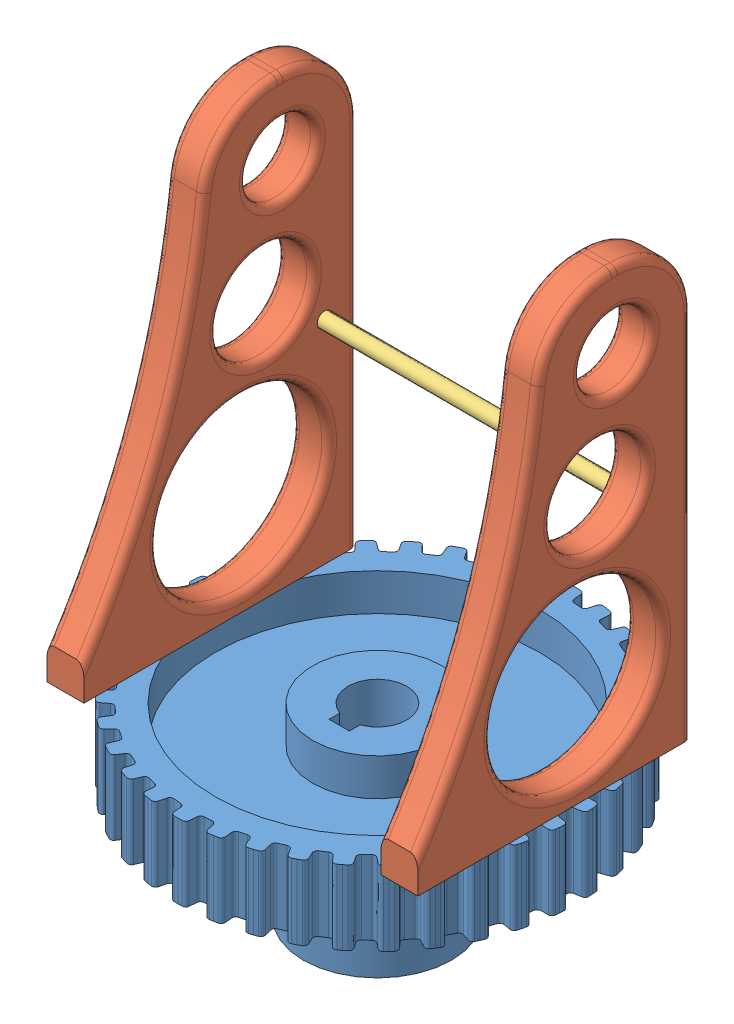
SolidWorks assembly Assem1, configuration Default. Lengths in mm.
Overall size (53.6 85 66.25).
4 component instances, 3 part files, 6 mates.
Components (placement in the parent):
- Part2-1: Part2 [Default] at (15.5294 18.4069 46.7581) size (53.6 25 53.71)
- Part3-1: Part3 [Default] at (-4.2228 58.4069 49.6898) x (0 0 1) z (-1 0 0) size (36.85 60 5.31)
- Part3-2: Part3 [Default] at (40.7772 58.4069 49.6898) x (0 0 1) z (-1 0 0) size (36.85 60 5.31)
- Part4-1: Part4 [Default] at (37.2017 57.8028 34.6908) x (0 0 1) z (-1 0 0) size (2 2 42)
Mates (geometry in assembly coordinates):
- Coincident1: coincident: plane of Part2-1 through (15.5294 28.4069 46.7581) normal (0 1 0); line of Part3-1 through (-9.2228 28.4069 30.6898) axis (0 0 1)
- Concentric1: concentric: circle of Part3-1; circle of Part3-2
- Parallel1: parallel: face of Part3-1; face of Part3-2
- Distance2: distance = 40 mm anti-aligned: plane of Part3-1 through (-4.2228 52.3392 56.8442) normal (1 0 0); plane of Part3-2 through (35.7772 52.3392 56.8442) normal (-1 0 0)
- Concentric2: concentric: circle of Part3-1; circle of Part3-2
- Coincident3: coincident: plane of Part2-1 through (15.5294 28.4069 46.7581) normal (0 1 0); line of Part3-2 through (40.7772 28.4069 30.6898) axis (0 0 1)
